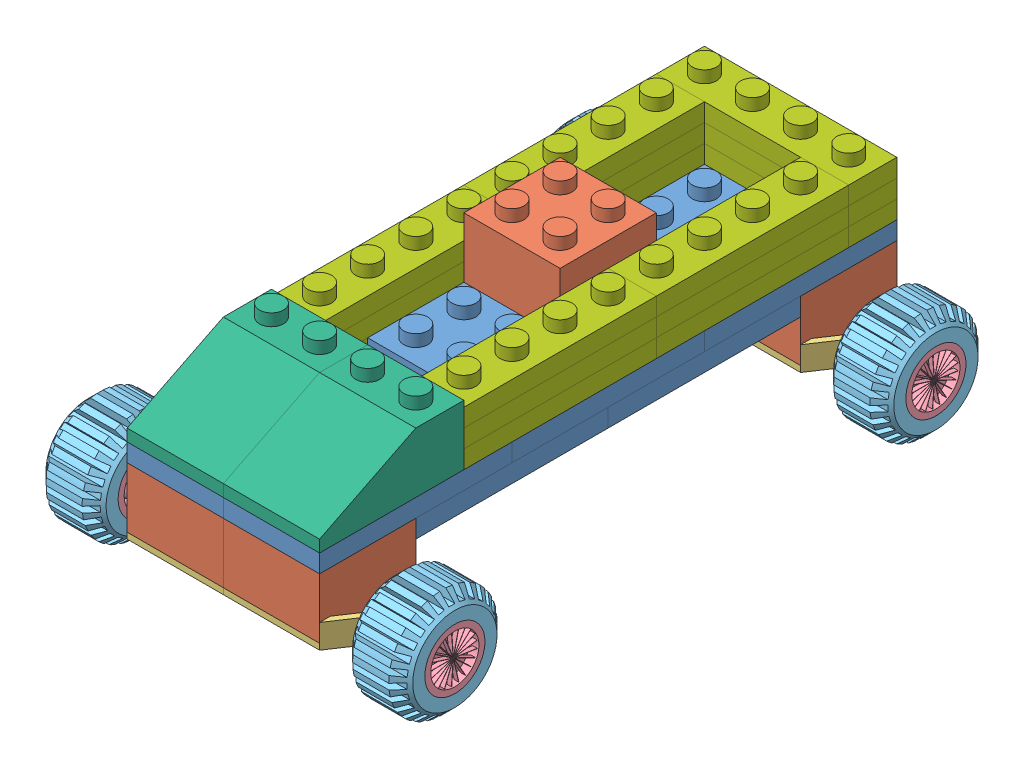
SolidWorks assembly auto volledig, configuration Default. Lengths in mm.
Overall size (61 36 98).
56 component instances, 7 part files, 27 mates.
Components (placement in the parent):
- auto+wielen-1: auto+wielen [Default] at (2.8156 6.5996 1.7642) size (61 23 98)
  - auto-1: auto [Default] at (17.9671 33.4037 81.0448) size (32 8 96)
    - blokje plat-1: blokje plat [Default] at (5.052 17.5943 26.9125) x (0 0 -1) z (1 0 0) size (32 5 16)
    - blokje plat-2: blokje plat [Default] at (5.052 17.5943 -5.0875) x (0 0 -1) z (1 0 0) size (32 5 16)
    - blokje plat-3: blokje plat [Default] at (5.052 17.5943 -37.0875) x (0 0 -1) z (1 0 0) size (32 5 16)
    - blokje plat-4: blokje plat [Default] at (21.052 17.5943 26.9125) x (0 0 -1) z (1 0 0) size (32 5 16)
    - blokje plat-5: blokje plat [Default] at (21.052 17.5943 -5.0875) x (0 0 -1) z (1 0 0) size (32 5 16)
    - blokje plat-6: blokje plat [Default] at (21.052 17.5943 -37.0875) x (0 0 -1) z (1 0 0) size (32 5 16)
    - blokje plat-7: blokje plat [Default] at (5.052 14.5943 -21.0875) x (0 0 -1) z (1 0 0) size (32 5 16)
    - blokje plat-8: blokje plat [Default] at (21.052 14.5943 -21.0875) x (0 0 -1) z (1 0 0) size (32 5 16)
    - blokje plat-9: blokje plat [Default] at (21.052 14.5943 10.9125) x (0 0 -1) z (1 0 0) size (32 5 16)
    - blokje plat-10: blokje plat [Default] at (5.052 14.5943 10.9125) x (0 0 -1) z (1 0 0) size (32 5 16)
  - wiel+blok-1: wiel+blok [Default] at (20.6514 35.2948 103.0331) size (30.5 20 18)
    - blokje klein-1: blokje klein [groter blokje] at (2.3677 9.2032 12.9242) size (16 12 16)
    - wielblok-1: wielblok [Default] at (2.3677 5.2032 12.9242) size (28 4 16)
    - velgen-1: velgen [Default] at (-15.1323 5.2032 12.9242) x (0 -1 0) z (0 0 1) size (10 10 10)
    - wielen-1: wielen [Default] at (-20.1323 5.2032 12.9242) x (0 0 -1) z (0 -1 0) size (18 10 17.99)
  - wiel+blok-2: wiel+blok [Default] at (41.3868 35.2948 128.8816) x (-1 0 0) z (0 0 -1) size (30.5 20 18)
    - blokje klein-1: blokje klein [groter blokje] at (2.3677 9.2032 12.9242) size (16 12 16)
    - wielblok-1: wielblok [Default] at (2.3677 5.2032 12.9242) size (28 4 16)
    - velgen-1: velgen [Default] at (-15.1323 5.2032 12.9242) x (0 -1 0) z (0 0 1) size (10 10 10)
    - wielen-1: wielen [Default] at (-20.1323 5.2032 12.9242) x (0 0 -1) z (0 -1 0) size (18 10 17.99)
  - wiel+blok-3: wiel+blok [Default] at (20.6514 35.2948 23.0331) size (30.5 20 18)
    - blokje klein-1: blokje klein [groter blokje] at (2.3677 9.2032 12.9242) size (16 12 16)
    - wielblok-1: wielblok [Default] at (2.3677 5.2032 12.9242) size (28 4 16)
    - velgen-1: velgen [Default] at (-15.1323 5.2032 12.9242) x (0 -1 0) z (0 0 1) size (10 10 10)
    - wielen-1: wielen [Default] at (-20.1323 5.2032 12.9242) x (0 0 -1) z (0 -1 0) size (18 10 17.99)
  - wiel+blok-4: wiel+blok [Default] at (41.3868 35.2948 48.8816) x (-1 0 0) z (0 0 -1) size (30.5 20 18)
    - blokje klein-1: blokje klein [groter blokje] at (2.3677 9.2032 12.9242) size (16 12 16)
    - wielblok-1: wielblok [Default] at (2.3677 5.2032 12.9242) size (28 4 16)
    - velgen-1: velgen [Default] at (-15.1323 5.2032 12.9242) x (0 -1 0) z (0 0 1) size (10 10 10)
    - wielen-1: wielen [Default] at (-20.1323 5.2032 12.9242) x (0 0 -1) z (0 -1 0) size (18 10 17.99)
- blokje schuin-1: blokje schuin [Default] at (25.8347 59.0976 113.7216) x (0 0 -1) z (1 0 0) size (24 12 16)
- blokje schuin-2: blokje schuin [Default] at (41.8347 59.0976 113.7216) x (0 0 -1) z (1 0 0) size (24 12 16)
- 3 blokjes op elkaar-1: 3 blokjes op elkaar [Default] at (19.649 46.8644 9.0055) size (32 11 8)
  - blokje plat half-1: blokje plat half [Default] at (14.1857 13.7332 24.716) size (32 5 8)
  - blokje plat half-2: blokje plat half [Default] at (14.1857 16.7332 24.716) size (32 5 8)
  - blokje plat half-3: blokje plat half [Default] at (14.1857 19.7332 24.716) size (32 5 8)
- 3 blokjes op elkaar-2: 3 blokjes op elkaar [Default] at (-2.8813 46.8644 67.9072) x (0 0 -1) z (1 0 0) size (32 11 8)
  - blokje plat half-1: blokje plat half [Default] at (14.1857 13.7332 24.716) size (32 5 8)
  - blokje plat half-2: blokje plat half [Default] at (14.1857 16.7332 24.716) size (32 5 8)
  - blokje plat half-3: blokje plat half [Default] at (14.1857 19.7332 24.716) size (32 5 8)
- 3 blokjes op elkaar-3: 3 blokjes op elkaar [Default] at (-2.8813 46.8644 99.9072) x (0 0 -1) z (1 0 0) size (32 11 8)
  - blokje plat half-1: blokje plat half [Default] at (14.1857 13.7332 24.716) size (32 5 8)
  - blokje plat half-2: blokje plat half [Default] at (14.1857 16.7332 24.716) size (32 5 8)
  - blokje plat half-3: blokje plat half [Default] at (14.1857 19.7332 24.716) size (32 5 8)
- 3 blokjes op elkaar-4: 3 blokjes op elkaar [Default] at (21.1187 46.8644 99.9072) x (0 0 -1) z (1 0 0) size (32 11 8)
  - blokje plat half-1: blokje plat half [Default] at (14.1857 13.7332 24.716) size (32 5 8)
  - blokje plat half-2: blokje plat half [Default] at (14.1857 16.7332 24.716) size (32 5 8)
  - blokje plat half-3: blokje plat half [Default] at (14.1857 19.7332 24.716) size (32 5 8)
- 3 blokjes op elkaar-5: 3 blokjes op elkaar [Default] at (21.1187 46.8644 67.9072) x (0 0 -1) z (1 0 0) size (32 11 8)
  - blokje plat half-1: blokje plat half [Default] at (14.1857 13.7332 24.716) size (32 5 8)
  - blokje plat half-2: blokje plat half [Default] at (14.1857 16.7332 24.716) size (32 5 8)
  - blokje plat half-3: blokje plat half [Default] at (14.1857 19.7332 24.716) size (32 5 8)
- blokje plat-1: blokje plat [Default] at (33.8347 60.5976 77.7216) x (0 0 -1) z (1 0 0) size (32 5 16)
- blokje klein-1: blokje klein [groter blokje] at (33.8347 67.0976 69.7216) size (16 12 16)
Mates (geometry in assembly coordinates):
- Coincident1: coincident anti-aligned: plane of auto+wielen-1/auto-1/blokje plat-1 through (25.8347 59.0976 109.7216) normal (0 1 0); plane of blokje schuin-1 through (25.8347 59.0976 113.7216) normal (0 -1 0)
- Coincident2: coincident aligned: plane of auto+wielen-1/auto-1/blokje plat-1 through (17.8347 59.0976 125.7216) normal (-1 0 0); plane of blokje schuin-1 through (17.8347 69.0976 125.7216) normal (-1 0 0)
- Coincident3: coincident aligned: plane of auto+wielen-1/auto-1/blokje plat-1 through (17.8347 59.0976 125.7216) normal (0 0 1); plane of blokje schuin-1 through (17.8347 69.0976 125.7216) normal (0 0 1)
- Coincident4: coincident aligned: plane of auto+wielen-1/auto-1/blokje plat-4 through (49.8347 59.0976 125.7216) normal (1 0 0); plane of blokje schuin-2 through (49.8347 69.0976 125.7216) normal (1 0 0)
- Coincident5: coincident anti-aligned: plane of auto+wielen-1/auto-1/blokje plat-4 through (41.8347 59.0976 109.7216) normal (0 1 0); plane of blokje schuin-2 through (41.8347 59.0976 113.7216) normal (0 -1 0)
- Coincident6: coincident aligned: plane of auto+wielen-1/auto-1/blokje plat-4 through (33.8347 59.0976 125.7216) normal (0 0 1); plane of blokje schuin-2 through (33.8347 69.0976 125.7216) normal (0 0 1)
- Coincident16: coincident anti-aligned: plane of auto+wielen-1/auto-1/blokje plat-6 through (41.8347 59.0976 45.7216) normal (0 1 0); plane of 3 blokjes op elkaar-1/blokje plat half-1 through (33.8347 59.0976 33.7216) normal (0 -1 0)
- Coincident17: coincident aligned: plane of auto+wielen-1/wiel+blok-4/blokje klein-1 through (49.8347 56.0976 29.7216) normal (0 0 -1); plane of 3 blokjes op elkaar-1/blokje plat half-2 through (17.8347 65.0976 29.7216) normal (0 0 -1)
- Coincident18: coincident aligned: plane of auto+wielen-1/auto-1/blokje plat-3 through (17.8347 59.0976 61.7216) normal (-1 0 0); plane of 3 blokjes op elkaar-1/blokje plat half-2 through (17.8347 65.0976 29.7216) normal (-1 0 0)
- Coincident19: coincident anti-aligned: plane of 3 blokjes op elkaar-1/blokje plat half-3 through (17.8347 68.0976 37.7216) normal (0 0 1); plane of 3 blokjes op elkaar-2/blokje plat half-2 through (17.8347 65.0976 37.7216) normal (0 0 -1)
- Coincident20: coincident aligned: plane of 3 blokjes op elkaar-1/blokje plat half-2 through (17.8347 65.0976 29.7216) normal (-1 0 0); plane of 3 blokjes op elkaar-2/blokje plat half-2 through (17.8347 65.0976 69.7216) normal (-1 0 0)
- Coincident21: coincident aligned: plane of 3 blokjes op elkaar-1/blokje plat half-3 through (33.8347 68.0976 33.7216) normal (0 1 0); plane of 3 blokjes op elkaar-2/blokje plat half-3 through (21.8347 68.0976 53.7216) normal (0 1 0)
- Coincident22: coincident anti-aligned: plane of auto+wielen-1/auto-1/blokje plat-2 through (25.8347 59.0976 77.7216) normal (0 1 0); plane of 3 blokjes op elkaar-3/blokje plat half-1 through (21.8347 59.0976 85.7216) normal (0 -1 0)
- Coincident23: coincident aligned: plane of 3 blokjes op elkaar-2/blokje plat half-3 through (17.8347 68.0976 69.7216) normal (-1 0 0); plane of 3 blokjes op elkaar-3/blokje plat half-3 through (17.8347 68.0976 101.7216) normal (-1 0 0)
- Coincident24: coincident anti-aligned: plane of blokje schuin-1 through (17.8347 69.0976 101.7216) normal (0 0 -1); plane of 3 blokjes op elkaar-3/blokje plat half-3 through (17.8347 68.0976 101.7216) normal (0 0 1)
- Coincident25: coincident anti-aligned: plane of auto+wielen-1/auto-1/blokje plat-5 through (41.8347 59.0976 77.7216) normal (0 1 0); plane of 3 blokjes op elkaar-4/blokje plat half-1 through (45.8347 59.0976 85.7216) normal (0 -1 0)
- Coincident26: coincident anti-aligned: plane of blokje schuin-2 through (33.8347 69.0976 101.7216) normal (0 0 -1); plane of 3 blokjes op elkaar-4/blokje plat half-3 through (41.8347 68.0976 101.7216) normal (0 0 1)
- Coincident27: coincident aligned: plane of auto+wielen-1/auto-1/blokje plat-4 through (49.8347 59.0976 125.7216) normal (1 0 0); plane of 3 blokjes op elkaar-4/blokje plat half-1 through (49.8347 62.0976 101.7216) normal (1 0 0)
- Coincident28: coincident aligned: plane of auto+wielen-1/auto-1/blokje plat-6 through (49.8347 59.0976 61.7216) normal (1 0 0); plane of 3 blokjes op elkaar-5/blokje plat half-3 through (49.8347 68.0976 69.7216) normal (1 0 0)
- Coincident29: coincident anti-aligned: plane of auto+wielen-1/auto-1/blokje plat-6 through (41.8347 59.0976 45.7216) normal (0 1 0); plane of 3 blokjes op elkaar-5/blokje plat half-1 through (45.8347 59.0976 53.7216) normal (0 -1 0)
- Coincident30: coincident anti-aligned: plane of 3 blokjes op elkaar-1/blokje plat half-3 through (17.8347 68.0976 37.7216) normal (0 0 1); plane of 3 blokjes op elkaar-5/blokje plat half-3 through (41.8347 68.0976 37.7216) normal (0 0 -1)
- Coincident32: coincident: plane of auto+wielen-1/auto-1/blokje plat-2 through (25.8347 59.0976 77.7216) normal (0 1 0); plane of blokje plat-1 through (33.8347 59.0976 67.0477) normal (0 -1 0)
- Coincident33: coincident: plane of 3 blokjes op elkaar-4/blokje plat half-2 through (41.8347 65.0976 101.7216) normal (-1 0 0); plane of blokje plat-1 through (41.8347 62.0976 83.0477) normal (1 0 0)
- Coincident34: coincident: line of auto+wielen-1/auto-1/blokje plat-1 through (33.8347 59.0976 93.7216) axis (-1 0 0); plane of blokje plat-1 through (25.8347 62.0976 93.7216) normal (0 0 1)
- Coincident35: coincident: plane of blokje plat-1 through (33.8347 62.0976 77.7216) normal (0 1 0); plane of blokje klein-1 through (33.8347 62.0976 69.7216) normal (0 -1 0)
- Coincident36: coincident: plane of 3 blokjes op elkaar-4/blokje plat half-3 through (41.8347 68.0976 101.7216) normal (-1 0 0); plane of blokje klein-1 through (41.8347 72.0976 61.7216) normal (1 0 0)
- Coincident37: coincident aligned: plane of blokje plat-1 through (25.8347 62.0976 61.7216) normal (0 0 -1); plane of blokje klein-1 through (25.8347 72.0976 61.7216) normal (0 0 -1)
